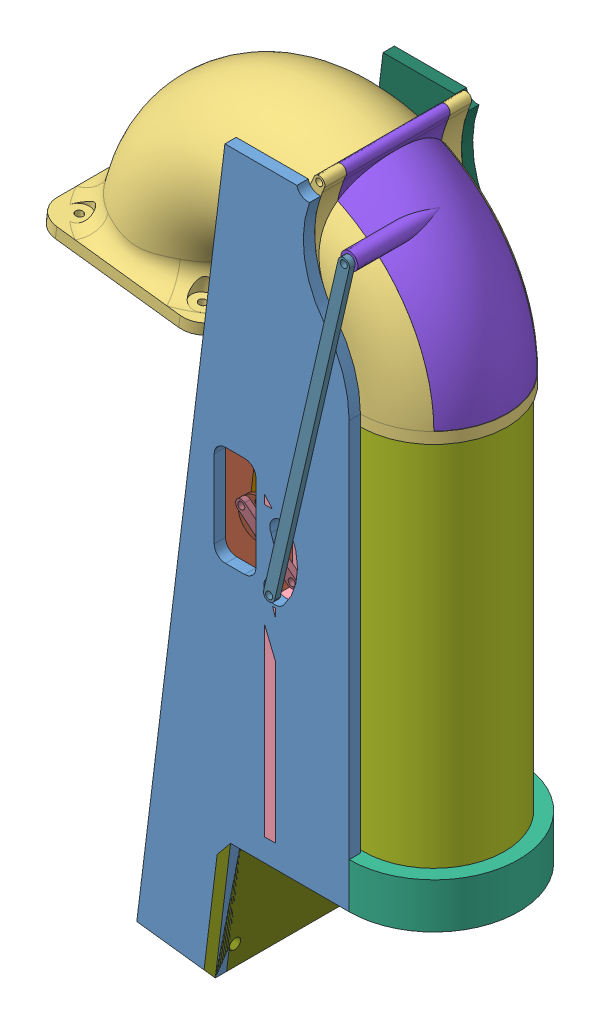
SolidWorks assembly Lift, configuration Default. Lengths in mm.
Overall size (225.36 415.4 98.42).
23 component instances, 16 part files, 40 mates.
Components (placement in the parent):
- Left Side-2: Left Side [Default] at (-74.4651 -231.6304 18.2556) size (119.38 408.79 6.35)
- Back-1: Back [Default] at (-98.0786 -200.3162 24.6056) x (0 0 -1) z (0.992546 -0.121869 0) size (95.25 358.8 6.35)
- Bend Vent-1: Bend Vent [Default] at (21.2991 103.3056 -23.0194) size (219.01 112.71 95.25)
- Inner Support-1: Inner Support [Default] at (-26.3259 -123.1833 24.6056) x (0 0 -1) z (1 0 0) size (95.25 222.25 6.35)
- Servo Support-1: Servo Support [Default] at (-58.0759 -107.3083 24.6056) x (1 0 0) z (0 1 0) size (38.1 95.25 6.35)
- Bottom Tube Support-1: Bottom Tube Support [Default] at (21.2991 -135.8833 -23.0194) x (1 0 0) z (0 1 0) size (88.9 95.25 27.05)
- Storage Tube-1: Storage Tube [Default] at (21.2991 103.3085 -23.0194) x (1 0 0) z (0 -1 0) size (79.38 79.38 220.14)
- Vent Door-1: Vent Door [Default] at (20.9595 103.2285 -23.0194) x (0.999994 -0.003354 0) z (0.003354 0.999994 0) size (71.14 76.81 104.37)
- Vent Servo Mount-1: Vent Servo Mount [Default] at (-67.6009 -4.2003 -13.9444) size (41.27 63.5 6.35)
- Tetrix Servo 180° (with Horn)-1: Tetrix Servo 180° (with Horn) [Default] at (-42.6759 16.9122 -7.5944) x (1 0 0) z (0 -1 0) size (22 47.52 56.6)
  - Tetrix Servo Body B-1: Tetrix Servo Body B [Default] at origin size (20 43.2 56.6)
  - Tetrix Servo Horn B-1: Tetrix Servo Horn B [Default] at (0 17.5 0) size (22 6.2 22)
  - Tetrix Servo Body Screw B-1: Tetrix Servo Body Screw B [Default] at (0 19.5 0) size (5.08 10.95 5.08)
  - Tetrix Servo Body Screw B-2: Tetrix Servo Body Screw B [Default] at (0 18.2 0) size (5.08 10.95 5.08)
- Vent Servo Horn-1: Vent Servo Horn [Default] at (-42.6759 16.9122 11.9056) x (0.775762 -0.631026 0) z (0 0 1) size (42.92 6.35 3.17)
- Tetrix Servo 180° (with Horn)-2: Tetrix Servo 180° (with Horn) [Default] at (-39.8209 -107.3083 -45.4394) x (1 0 0) z (0 0 -1) size (22 47.52 56.6)
  - Tetrix Servo Body B-1: Tetrix Servo Body B [Default] at origin size (20 43.2 56.6)
  - Tetrix Servo Horn B-1: Tetrix Servo Horn B [Default] at (0 17.5 0) size (22 6.2 22)
  - Tetrix Servo Body Screw B-1: Tetrix Servo Body Screw B [Default] at (0 19.5 0) size (5.08 10.95 5.08)
  - Tetrix Servo Body Screw B-2: Tetrix Servo Body Screw B [Default] at (0 18.2 0) size (5.08 10.95 5.08)
- Vent Servo Connecting Rod-2: Vent Servo Connecting Rod [Default] at (-20.5085 -1.1193 24.6056) x (0.224392 0.974499 0) z (0 0 1) size (193.29 6.35 3.17)
- Right Side-1: Right Side [Default] at (-74.4651 -231.6304 -70.6444) size (119.38 408.79 6.35)
- Bottom Back-1: Bottom Back [Default] at (-57.397 -233.7261 18.2556) x (0 0 -1) z (0.992546 -0.121869 0) size (95.25 70.37 6.35)
Mates (geometry in assembly coordinates):
- Coincident5: coincident aligned: plane of Back-1 through (-98.0786 -200.3162 24.6056) normal (-0.992546 0.121869 0); plane of Left Side-2 through (-98.0786 -200.3162 24.6056) normal (-0.992546 0.121869 0)
- Coincident7: coincident aligned: plane of Left Side-2 through (-74.4651 -231.6304 24.6056) normal (0 0 1); plane of Back-1 through (-91.7759 -201.0901 24.6056) normal (0 0 1)
- Coincident8: coincident: plane of Left Side-2 through (21.2991 -135.8833 24.6056) normal (1 0 0); axis of Bend Vent-1 through (21.2991 96.9556 -23.0194) axis (0 1 0)
- Distance3: distance = 307.975 mm: axis of Bend Vent-1 through (-43.7884 103.3056 23.5697) axis (0 0 -1); plane of Back-1 through (-91.7759 -201.0901 24.6056) normal (-0.121869 -0.992546 0)
- Distance4: distance = 41.275 mm: axis of Bend Vent-1 through (21.2991 96.9556 -23.0194) axis (0 1 0); plane of Left Side-2 through (-74.4651 -231.6304 18.2556) normal (0 0 -1)
- Coincident16: coincident aligned: plane of Inner Support-1 through (-19.9759 -123.1833 24.6056) normal (1 0 0); plane of Servo Support-1 through (-19.9759 -100.9583 24.6056) normal (1 0 0)
- Coincident17: coincident aligned: plane of Servo Support-1 through (-58.0759 -100.9583 24.6056) normal (0 0 1); plane of Left Side-2 through (-74.4651 -231.6304 24.6056) normal (0 0 1)
- Distance8: distance = 15.875 mm aligned: plane of Inner Support-1 through (-19.9759 -123.1833 24.6056) normal (0 -1 0); plane of Servo Support-1 through (-58.0759 -107.3083 24.6056) normal (0 -1 0)
- Coincident20: coincident anti-aligned: plane of Inner Support-1 through (-19.9759 -123.1833 24.6056) normal (1 0 0); plane of Bottom Tube Support-1 through (-19.9759 -110.4833 18.2556) normal (-1 0 0)
- Coincident22: coincident anti-aligned: plane of Bottom Tube Support-1 through (21.2991 -116.8333 -23.0194) normal (0 1 0); plane of Storage Tube-1 through (21.2991 -116.8333 -23.0194) normal (0 -1 0)
- Concentric1: concentric aligned: cylinder of Bottom Tube Support-1 through (21.2991 -116.8333 -23.0194) axis (0 1 0) radius 39.6875; cylinder of Storage Tube-1 through (21.2991 -116.8333 -23.0194) axis (0 1 0) radius 39.6875
- Concentric2: concentric anti-aligned: cylinder of Bend Vent-1 through (-1.8702 204.5051 105.8096) axis (0 0 -1) radius 1.9844; cylinder of Vent Door-1 through (-1.8702 204.5051 -52.2052) axis (0 0 1) radius 1.9844
- Coincident23: coincident anti-aligned: plane of Bend Vent-1 through (-15.4399 193.2157 6.1664) normal (0 0 -1); plane of Vent Door-1 through (-1.8702 204.5051 6.1664) normal (0 0 1)
- Coincident24: coincident anti-aligned: plane of Back-1 through (-91.7759 -201.0901 24.6056) normal (0.992546 -0.121869 0); plane of Vent Servo Mount-1 through (-67.6009 -4.2003 -7.5944) normal (-0.992546 0.121869 0)
- Coincident25: coincident anti-aligned: plane of Inner Support-1 through (-26.3259 -123.1833 24.6056) normal (-1 0 0); plane of Vent Servo Mount-1 through (-26.3259 -4.2003 -7.5944) normal (1 0 0)
- Coincident27: coincident anti-aligned: plane of Vent Servo Mount-1 through (-67.6009 6.9122 -7.5944) normal (0 1 0); plane of Tetrix Servo 180° (with Horn)-1/Tetrix Servo Body B-1 through (-32.6759 6.9122 -0.1944) normal (0 -1 0)
- Coincident29: coincident anti-aligned: plane of Vent Servo Mount-1 through (-67.6009 -4.2003 -7.5944) normal (0 0 1); plane of Tetrix Servo 180° (with Horn)-1/Tetrix Servo Body B-1 through (-50.5509 1.8122 -7.5944) normal (0 0 -1)
- Coincident28: coincident anti-aligned: plane of Vent Servo Mount-1 through (-32.6759 -4.2003 -7.5944) normal (-1 0 0); plane of Tetrix Servo 180° (with Horn)-1/Tetrix Servo Body B-1 through (-32.6759 46.9122 -0.1944) normal (1 0 0)
- Coincident31: coincident anti-aligned: plane of Tetrix Servo 180° (with Horn)-1/Tetrix Servo Horn B-1 through (-42.6759 16.9122 11.9056) normal (0 0 1); plane of Vent Servo Horn-1 through (-20.5085 -1.1193 11.9056) normal (0 0 -1)
- LimitAngle3: limit planar angle = 0.887922 rad aligned: plane of Vent Servo Horn-1 through (-46.8785 24.4235 15.0806) normal (0.631026 0.775762 0); plane of Tetrix Servo 180° (with Horn)-1/Tetrix Servo Body B-1 through (-33.7759 40.5922 3.2056) normal (1 0 0)
- Distance10: distance = 3.175 mm anti-aligned: plane of Vent Servo Horn-1 through (-20.5085 -1.1193 15.0806) normal (0 0 1); plane of Left Side-2 through (-74.4651 -231.6304 18.2556) normal (0 0 -1)
- Coincident35: coincident anti-aligned: plane of Servo Support-1 through (-58.0759 -107.3083 24.6056) normal (0 -1 0); plane of Tetrix Servo 180° (with Horn)-2/Tetrix Servo Body B-1 through (-47.6959 -107.3083 -60.5394) normal (0 1 0)
- Coincident36: coincident anti-aligned: plane of Servo Support-1 through (-49.8209 -100.9583 -55.4394) normal (1 0 0); plane of Tetrix Servo 180° (with Horn)-2/Tetrix Servo Body B-1 through (-49.8209 -114.7083 -15.4394) normal (-1 0 0)
- Coincident38: coincident anti-aligned: plane of Servo Support-1 through (-49.8209 -100.9583 -55.4394) normal (0 0 1); plane of Tetrix Servo 180° (with Horn)-2/Tetrix Servo Body B-1 through (-29.8209 -114.7083 -55.4394) normal (0 0 -1)
- Coincident43: coincident: axis of Tetrix Servo 180° (with Horn)-1/Tetrix Servo Body Screw B-1 through (-42.6759 16.9122 14.2537) axis (0 0 -1); point of Vent Servo Horn-1
- Coincident44: coincident anti-aligned: plane of Left Side-2 through (-74.4651 -231.6304 24.6056) normal (0 0 1); plane of Vent Servo Connecting Rod-2 through (-20.5085 -1.1193 24.6056) normal (0 0 -1)
- Concentric3: concentric aligned: cylinder of Vent Door-1 through (21.4403 181.0574 24.6056) axis (0 0 -1) radius 1.9844; cylinder of Vent Servo Connecting Rod-2 through (21.4403 181.0574 27.7806) axis (0 0 -1) radius 1.9844
- Concentric4: concentric aligned: cylinder of Vent Servo Horn-1 through (-20.5085 -1.1193 15.0806) axis (0 0 -1) radius 1.9844; cylinder of Vent Servo Connecting Rod-2 through (-20.5085 -1.1193 27.7806) axis (0 0 -1) radius 1.9844
- Coincident45: coincident aligned: plane of Back-1 through (-91.7759 -201.0901 -70.6444) normal (0 0 -1); plane of Inner Support-1 through (-19.9759 -123.1833 -70.6444) normal (0 0 -1)
- Coincident46: coincident aligned: plane of Left Side-2 through (-53.9599 -205.7333 24.6056) normal (-0.121869 -0.992546 0); plane of Back-1 through (-91.7759 -201.0901 24.6056) normal (-0.121869 -0.992546 0)
- Concentric5: concentric aligned: cylinder of Bend Vent-1 through (21.2991 96.9556 -23.0194) axis (0 1 0) radius 39.6875; cylinder of Storage Tube-1 through (21.2991 -116.8333 -23.0194) axis (0 1 0) radius 39.6875
- Coincident47: coincident aligned: plane of Left Side-2 through (21.2991 -135.8833 24.6056) normal (0 -1 0); plane of Bottom Tube Support-1 through (21.2991 -135.8833 -23.0194) normal (0 -1 0)
- Coincident48: coincident aligned: plane of Inner Support-1 through (-19.9759 -123.1833 24.6056) normal (0 -1 0); plane of Bottom Tube Support-1 through (-19.9759 -123.1833 24.6056) normal (0 -1 0)
- Coincident49: coincident aligned: plane of Back-1 through (-91.7759 -201.0901 -70.6444) normal (0 0 -1); plane of Right Side-1 through (-74.4651 -231.6304 -70.6444) normal (0 0 -1)
- Coincident50: coincident aligned: plane of Back-1 through (-91.7759 -201.0901 24.6056) normal (-0.121869 -0.992546 0); plane of Right Side-1 through (-53.9599 -205.7333 -64.2944) normal (-0.121869 -0.992546 0)
- Coincident51: coincident aligned: plane of Back-1 through (-98.0786 -200.3162 24.6056) normal (-0.992546 0.121869 0); plane of Right Side-1 through (-98.0786 -200.3162 -64.2944) normal (-0.992546 0.121869 0)
- InPlace1: in place: plane of Left Side-2 through (-45.3834 -135.8833 24.6056) normal (0.992546 -0.121869 0); plane of ? through (-28.2728 3.4715 0) normal (0.992546 -0.121869 0); moOrthogonalPlaneRef_w of Left Side-2 through (-45.3834 -135.8833 24.6056) normal (0.992546 -0.121869 0); line of ? through (-55 -28.2728 3.4715) axis (0 0.121869 0.992546); plane of Left Side-2 through (-45.3834 -135.8833 24.6056) normal (0.992546 -0.121869 0); unknown of ?; plane of Left Side-2 through (-45.3834 -135.8833 24.6056) normal (0.992546 -0.121869 0); unknown of Bottom Back-1
- Coincident52: coincident aligned: plane of Left Side-2; plane of Bottom Back-1
- Coincident53: coincident aligned: plane of Left Side-2 through (-57.397 -233.7261 18.2556) normal (0.121869 0.992546 0); unknown of Bottom Back-1
- Coincident54: coincident anti-aligned: plane of Left Side-2 through (-57.397 -233.7261 18.2556) normal (0 0 1); unknown of Bottom Back-1
